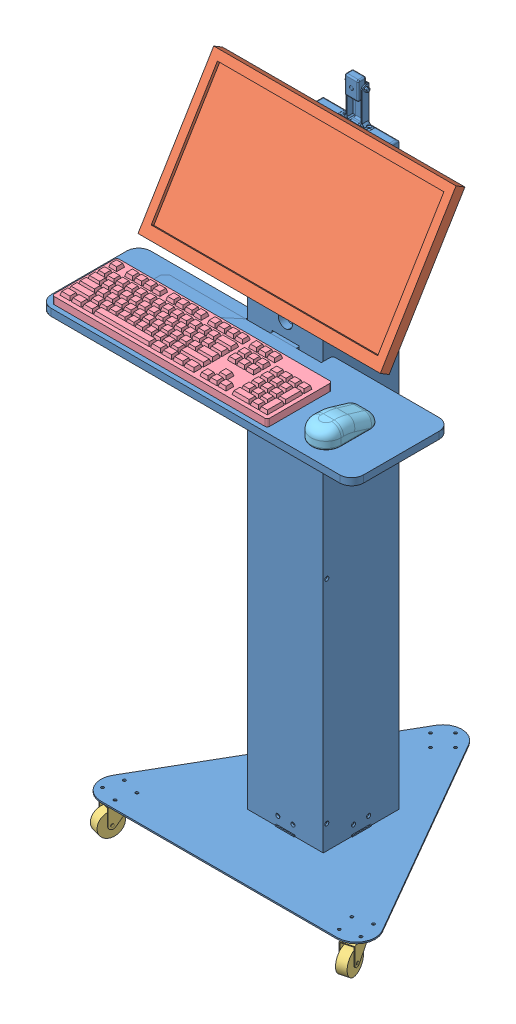
SolidWorks assembly kiosk, configuration Default. Lengths in mm.
Overall size (660 1383.55 563.01).
9 component instances, 7 part files, 15 mates.
Components (placement in the parent):
- kiosk-1: kiosk [camera_alta] at (-35.0319 -614.2692 11.6776) size (660 1313.05 563.01)
- raspberry_display-1: raspberry_display [Default] at (-35.0319 489.7571 22.1221) x (1 0 0) z (0 0.5 0.866025) size (110.8 193 40.1) (hidden)
- monitor_asus_VP228-1: monitor_asus_VP228 [Default] at (-35.0319 510.8087 67.1109) x (1 0 0) z (0 0.519548 0.854441) size (512 308 50.48)
- roda-1: roda [Default] at (-285.0319 -617.2692 191.6776) x (0.965926 0 0.258819) z (-0.258819 0 0.965926) size (50 70.5 70)
- roda-2: roda [Default] at (214.9681 -617.2692 191.6776) x (0.965926 0 -0.258819) z (0.258819 0 0.965926) size (50 70.5 70)
- roda-3: roda [Default] at (-35.0319 -617.2692 -241.3351) x (0.707107 0 0.707107) z (-0.707107 0 0.707107) size (50 70.5 70)
- keyboard-1: keyboard [Default] at (-347.3283 301.001 272.8071) size (455 22 136.98)
- mouse-1: mouse [Default] at (190.5746 285.9882 189.5174) size (63 38 114.97)
- fan-1: fan [Default] at (-35.0319 359.3571 -0.8224) x (-1 0 0) z (0 1 0) size (92 92 25.5)
Mates (geometry in assembly coordinates):
- Coincident1: coincident: point of assembly; point of kiosk-1; moEndPointRef_w of raspberry_display-1
- Coincident2: coincident: point of assembly; point of kiosk-1; moEndPointRef_w of raspberry_display-1
- Coincident3: coincident anti-aligned: plane of raspberry_display-1 through (12.3681 413.1139 66.3721) normal (0 0.5 0.866025); plane of monitor_asus_VP228-1 through (-291.0319 447.8424 46.3216) normal (0 -0.5 -0.866025)
- Coincident4: coincident aligned: circle of kiosk-1; circle of monitor_asus_VP228-1
- Coincident5: coincident aligned: circle of kiosk-1; circle of monitor_asus_VP228-1
- Coincident6: coincident: point of kiosk-1; point of kiosk-shelf_big-1
- Coincident7: coincident aligned: circle of kiosk-1; circle of roda-1
- Coincident8: coincident aligned: circle of kiosk-1; circle of roda-1
- Coincident9: coincident aligned: circle of kiosk-1; circle of roda-2
- Coincident10: coincident aligned: circle of kiosk-1; circle of roda-2
- Coincident11: coincident aligned: circle of kiosk-1; circle of roda-3
- Coincident12: coincident aligned: circle of kiosk-1; circle of roda-3
- Concentric2: concentric aligned: circle of kiosk-1; circle of monitor_asus_VP228-1
- Coincident13: coincident anti-aligned: circle of kiosk-1; circle of fan-1
- Parallel1: parallel aligned: plane of kiosk-1 through (-108.0319 -614.2692 -53.3224) normal (0 0 -1); plane of fan-1 through (10.9681 384.8571 -46.8224) normal (0 0 -1)
